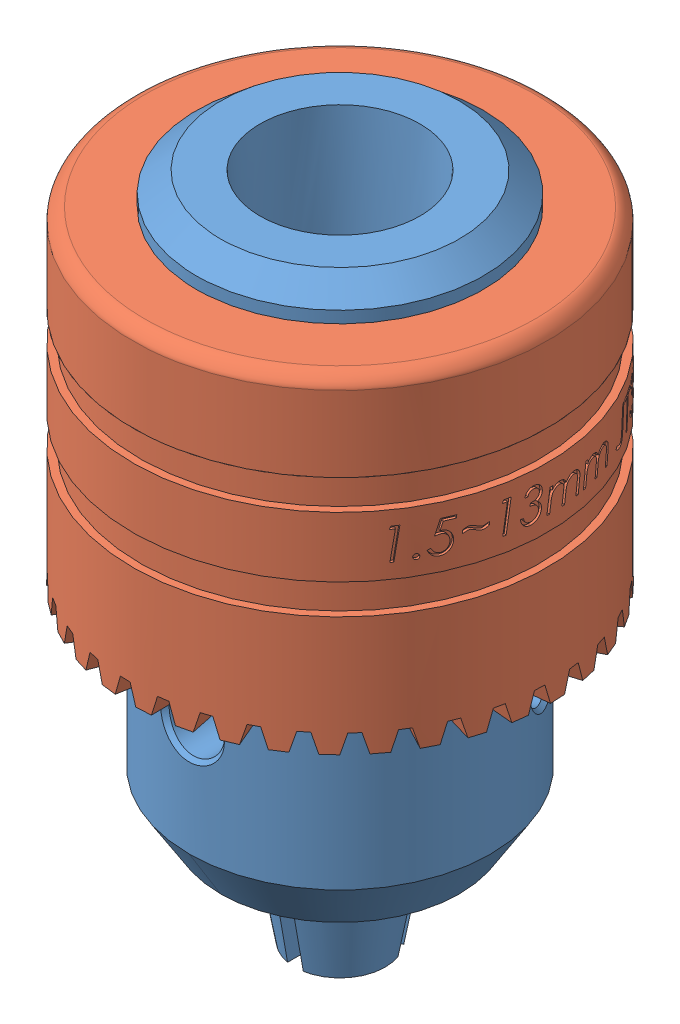
SolidWorks assembly Part4, configuration Default. Lengths in mm.
Overall size (48.21 67.48 48.21).
2 component instances, 2 part files, 2 mates.
Components (placement in the parent):
- Part4I-1: Part4I [Default] at (21.935 23.3622 61.566) size (30.48 67.48 30.48)
- Part4II-1: Part4II [Default] at (21.935 43.6822 61.566) x (0.990468 0 -0.13774) z (0.13774 0 0.990468) size (42.73 33.79 42.73)
Mates (geometry in assembly coordinates):
- Concentric1: concentric: cylinder of Part4I-1 through (21.935 43.6822 61.566) axis (0 1 0) radius 14.5; cylinder of Part4II-1 through (21.935 92.6617 61.566) axis (0 -1 0) radius 14.478
- Coincident1: coincident anti-aligned: plane of Part4I-1 through (21.935 43.6822 61.566) normal (0 1 0); plane of Part4II-1 through (21.935 43.6822 61.566) normal (0 -1 0)
